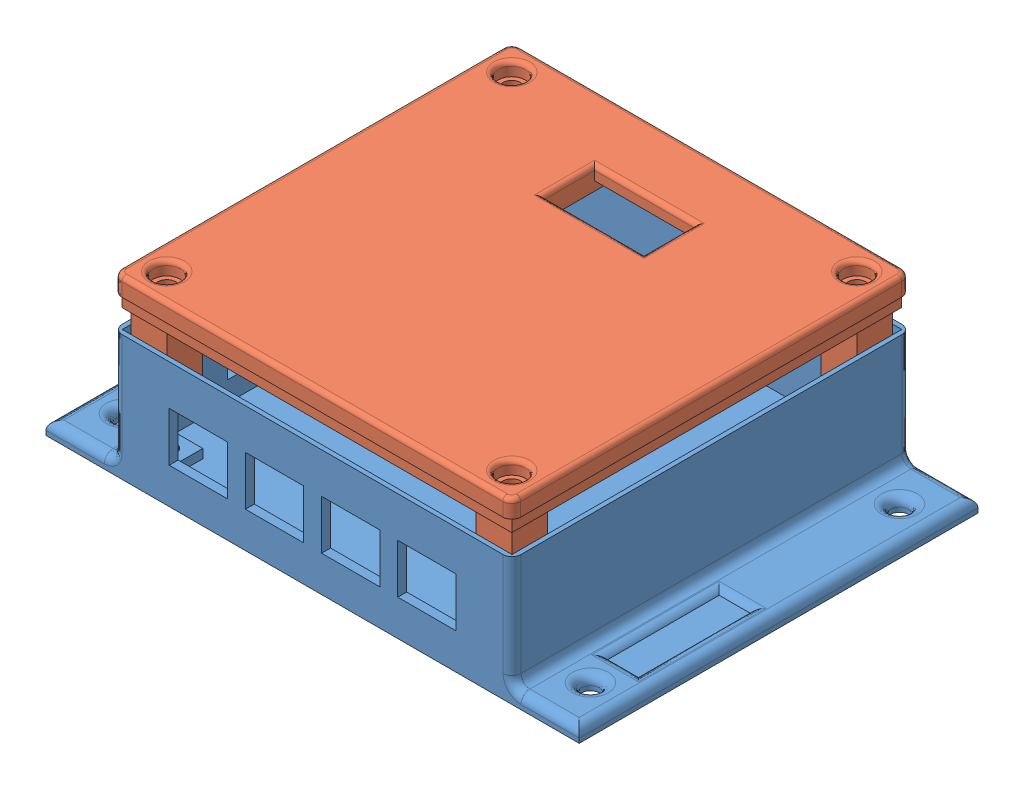
SolidWorks assembly JDJ_p1_Assem, configuration Default. Lengths in mm.
Overall size (119 38.99 89.21).
2 component instances, 2 part files, 0 mates.
Components (placement in the parent):
- JDJ_P1-2: JDJ_P1 [Default] at origin size (119 28 89)
- JDJ_P1_TOP-1: JDJ_P1_TOP [Default] at (-0.2545 33.9935 -0.2059) size (89 24 89)
